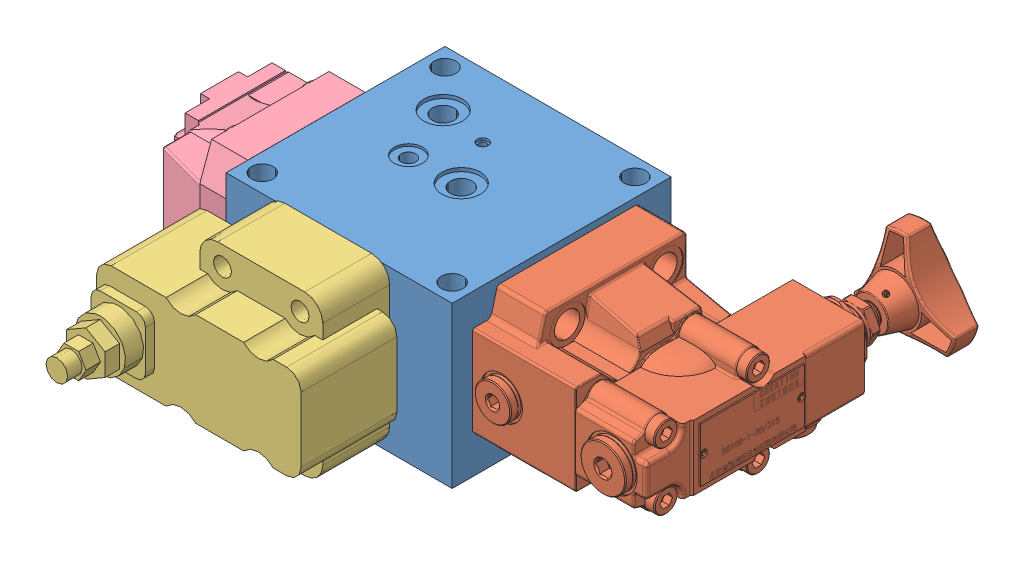
SolidWorks assembly 装配体1, configuration 默认. Lengths in mm.
Overall size (296.76 90.35 288.86).
4 component instances, 4 part files, 10 mates.
Components (placement in the parent):
- 3压力块(2)(1)-1: 3压力块(2)(1) [默认] at origin size (125 88.7 121)
- YF310B溢流阀-1: YF310B溢流阀 [默认] at (88.2535 2.55 -120.5177) x (0 0 -1) z (0 -1 0) size (184.64 107.74 78)
- 减压阀-1: 减压阀 [Default] at (-8.55 3 99.5) x (0 -1 0) z (0 0 -1) size (88 113 99)
- AF3E10B单向阀-1: AF3E10B单向阀 [默认] at (-88.1022 2.9 20.3906) x (0 0 1) z (0 -1 0) size (78 65.1 85)
Mates (geometry in assembly coordinates):
- 同心3: concentric aligned: circle of 3压力块(2)(1)-1; circle of YF310B溢流阀-1
- 同心4: concentric aligned: circle of 3压力块(2)(1)-1; circle of YF310B溢流阀-1
- 同心5: concentric anti-aligned: circle of 3压力块(2)(1)-1; circle of YF310B溢流阀-1
- 重合1: coincident anti-aligned: plane of 3压力块(2)(1)-1 through (60 0 0) normal (1 0 0); plane of YF310B溢流阀-1 through (60 -34.45 35.9141) normal (-1 0 0)
- 同心15: concentric aligned: circle of 3压力块(2)(1)-1; circle of 减压阀-1
- 同心18: concentric aligned: circle of 3压力块(2)(1)-1; circle of 减压阀-1
- 重合2: coincident anti-aligned: plane of 3压力块(2)(1)-1 through (-65 45.35 62.5) normal (0 0 1); plane of 减压阀-1 through (-8.55 3 62.5) normal (0 0 -1)
- 同心30: concentric aligned: circle of 3压力块(2)(1)-1; circle of AF3E10B单向阀-1
- 平行2: parallel aligned: plane of 3压力块(2)(1)-1 through (0 45.35 0) normal (0 1 0); plane of AF3E10B单向阀-1 through (-115 45.4 -14.3985) normal (0 1 0)
- 重合6: coincident anti-aligned: plane of 3压力块(2)(1)-1 through (-65 45.35 62.5) normal (-1 0 0); plane of AF3E10B单向阀-1 through (-65 2.9 18.05) normal (1 0 0)
